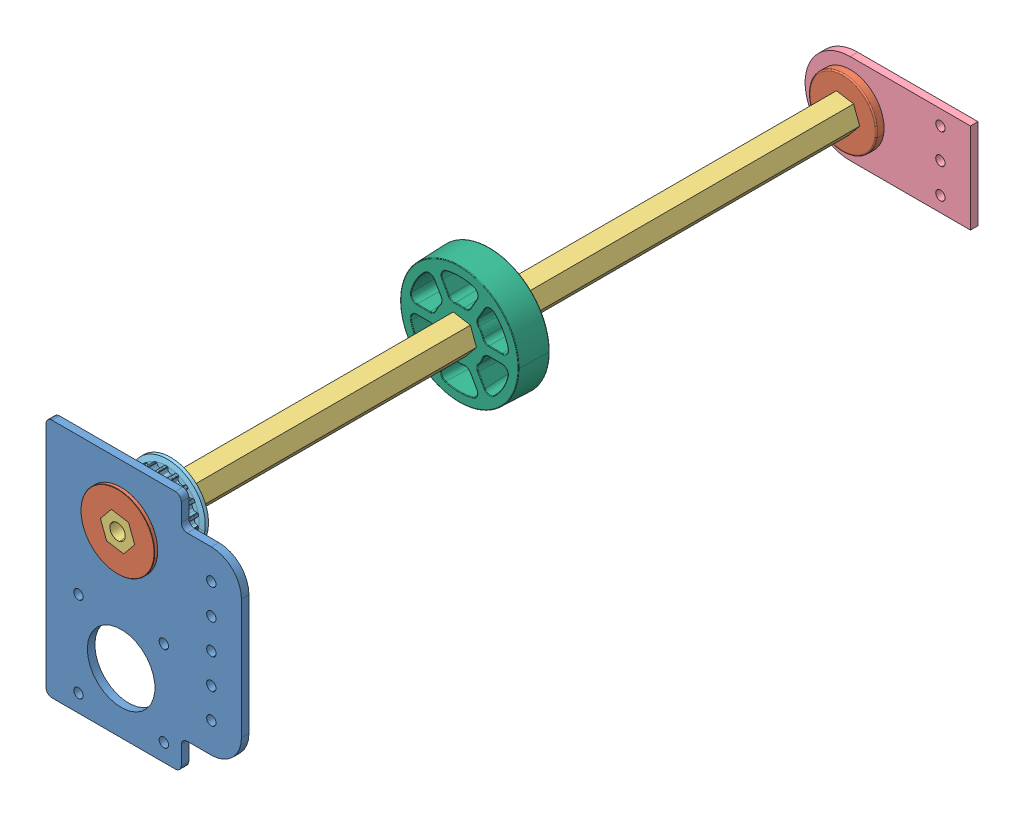
SolidWorks assembly funnel_wheel, configuration Default. Lengths in mm.
Overall size (82.55 101.7 314.2).
7 component instances, 6 part files, 16 mates.
Components (placement in the parent):
- funnel_wheel_mounting_bracket-1: funnel_wheel_mounting_bracket [Default] at (-57.2277 35.9236 115.9425) size (82.55 101.6 3.17)
- .500 Inch Hex Bearing - DB-1: .500 Inch Hex Bearing - DB [Default] at (-57.2277 86.7236 112.7142) x (0.986688 -0.162624 0) z (0 0 1) size (31.12 31.12 7.93)
- center_hex_shaft-1: center_hex_shaft [funnel wheel hex] at (-57.2277 86.7236 -36.4575) x (-0.906705 -0.421766 0) z (0.421766 -0.906705 0) size (13.21 314.2 14.62)
- .500 Inch Hex Bearing - DB-2: .500 Inch Hex Bearing - DB [Default] at (-57.2277 86.7236 -185.6292) x (-0.986688 0.162624 0) z (0 0 -1) size (31.12 31.12 7.93)
- funnel_wheel_mounting_bracket_without_motor_mount-1: funnel_wheel_mounting_bracket_without_motor_mount [Default] at (-57.2277 86.7236 -192.0325) size (69.85 38.1 3.17)
- 18T x 9mm Wide Double Flange Aluminum Pulley (HTD 5mm, 1_2” Hex Bore) (217-3225).step-1: 18T x 9mm Wide Double Flange Aluminum Pulley (HTD 5mm, 1_2” Hex Bore) (217-3225).step [Default] at (-57.2277 86.7236 105.4642) x (0.986688 -0.162624 0) z (0 0 1) size (32 32 14.5)
- 2inWheels.step-1: 2inWheels.step [Default] at (-57.2277 86.7236 -36.4575) x (0.99999 -0.004439 0) z (0 0 1) size (50.78 50.78 12.7)
Mates (geometry in assembly coordinates):
- Concentric1: concentric aligned: cylinder of funnel_wheel_mounting_bracket-1 through (-57.2277 86.7236 119.1175) axis (0 0 -1) radius 14.2875; cylinder of .500 Inch Hex Bearing - DB-1 through (-57.2277 86.7236 120.6415) axis (0 0 -1) radius 14.2875
- Coincident1: coincident anti-aligned: plane of funnel_wheel_mounting_bracket-1 through (-57.2277 35.9236 119.1175) normal (0 0 1); plane of .500 Inch Hex Bearing - DB-1 through (-43.4437 84.4517 119.1175) normal (0 0 -1)
- Coincident2: coincident anti-aligned: plane of .500 Inch Hex Bearing - DB-1 through (-64.4624 87.916 120.6415) normal (0.773185 -0.634181 0); plane of center_hex_shaft-1 through (-64.4624 87.916 -193.5565) normal (-0.773185 0.634181 0)
- Coincident3: coincident anti-aligned: plane of .500 Inch Hex Bearing - DB-1 through (-59.8124 93.5852 120.6415) normal (-0.162624 -0.986688 0); plane of center_hex_shaft-1 through (-59.8124 93.5852 -193.5565) normal (0.162624 0.986688 0)
- Coincident4: coincident aligned: plane of .500 Inch Hex Bearing - DB-1 through (-41.8773 84.1935 120.6415) normal (0 0 1); plane of center_hex_shaft-1 through (-57.2277 86.7236 120.6415) normal (0 0 1)
- Distance1: distance = 304.8 mm anti-aligned: plane of funnel_wheel_mounting_bracket-1 through (-57.2277 35.9236 115.9425) normal (0 0 -1); plane of funnel_wheel_mounting_bracket_without_motor_mount-1 through (-57.2277 86.7236 -188.8575) normal (0 0 1)
- Coincident6: coincident anti-aligned: plane of .500 Inch Hex Bearing - DB-2 through (-71.0117 88.9954 -192.0325) normal (0 0 1); plane of funnel_wheel_mounting_bracket_without_motor_mount-1 through (-57.2277 86.7236 -192.0325) normal (0 0 -1)
- Concentric2: concentric anti-aligned: cylinder of .500 Inch Hex Bearing - DB-2 through (-57.2277 86.7236 -193.5565) axis (0 0 1) radius 14.2875; cylinder of funnel_wheel_mounting_bracket_without_motor_mount-1 through (-57.2277 86.7236 -188.8575) axis (0 0 -1) radius 14.2875
- Coincident7: coincident anti-aligned: plane of center_hex_shaft-1 through (-64.4624 87.916 -193.5565) normal (-0.773185 0.634181 0); plane of .500 Inch Hex Bearing - DB-2 through (-59.8124 93.5852 -193.5565) normal (0.773185 -0.634181 0)
- Coincident8: coincident anti-aligned: plane of center_hex_shaft-1 through (-61.8777 81.0543 -193.5565) normal (-0.935809 -0.352508 0); plane of .500 Inch Hex Bearing - DB-2 through (-64.4624 87.916 -193.5565) normal (0.935809 0.352508 0)
- Parallel1: parallel aligned: plane of funnel_wheel_mounting_bracket-1 through (-57.2277 112.1236 119.1175) normal (0 1 0); plane of funnel_wheel_mounting_bracket_without_motor_mount-1 through (-57.2277 105.7736 -188.8575) normal (0 1 0)
- Coincident10: coincident anti-aligned: plane of .500 Inch Hex Bearing - DB-1 through (-57.2277 86.7236 112.7142) normal (0 0 -1); plane of 18T x 9mm Wide Double Flange Aluminum Pulley (HTD 5mm, 1_2” Hex Bore) (217-3225).step-1 through (-57.2277 86.7236 112.7142) normal (0 0 1)
- Coincident11: coincident anti-aligned: plane of center_hex_shaft-1 through (-64.4624 87.916 -193.5565) normal (-0.773185 0.634181 0); plane of 18T x 9mm Wide Double Flange Aluminum Pulley (HTD 5mm, 1_2” Hex Bore) (217-3225).step-1 through (-62.1374 90.7506 112.7142) normal (0.773185 -0.634181 0)
- Coincident12: coincident anti-aligned: plane of center_hex_shaft-1 through (-59.8124 93.5852 -193.5565) normal (0.162624 0.986688 0); plane of 18T x 9mm Wide Double Flange Aluminum Pulley (HTD 5mm, 1_2” Hex Bore) (217-3225).step-1 through (-56.195 92.989 112.7142) normal (-0.162624 -0.986688 0)
- Concentric3: concentric anti-aligned: cylinder of .500 Inch Hex Bearing - DB-1 through (-57.2277 86.7236 120.6415) axis (0 0 -1) radius 14.2875; cone of 2inWheels.step-1 through (-57.2277 86.7236 -36.4575) axis (0 0 1)
- Distance2: distance = 139.7 mm anti-aligned: plane of 2inWheels.step-1 through (-57.2277 86.7236 -23.7575) normal (0 0 1); plane of funnel_wheel_mounting_bracket-1 through (-57.2277 35.9236 115.9425) normal (0 0 -1)
